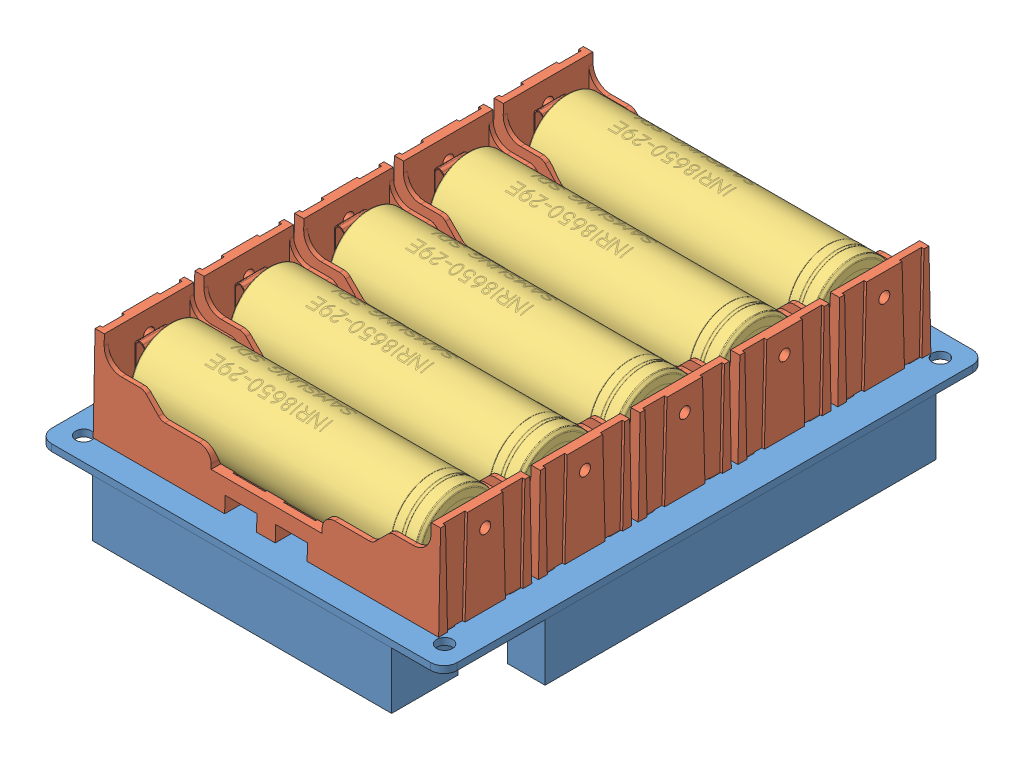
SolidWorks assembly 302 Dayton Audio KAB-BE Battery Board, configuration Default. Lengths in mm.
Overall size (91.5 36.02 122.2).
11 component instances, 3 part files, 16 mates.
Components (placement in the parent):
- 301 Dayton Audio KAB-BE PCB-1: 301 Dayton Audio KAB-BE PCB [Default] at origin size (91.5 14.55 122.2)
- single 18650 battery holder-1: single 18650 battery holder [Défaut] at (0 3.608 54.3158) x (0 0 1) z (-1 0 0) size (21 21.36 77.92)
- single 18650 battery holder-2: single 18650 battery holder [Défaut] at (0 3.608 -31.8158) x (0 0 -1) z (1 0 0) size (21 21.36 77.92)
- single 18650 battery holder-3: single 18650 battery holder [Défaut] at (0 3.608 31.8158) x (0 0 1) z (-1 0 0) size (21 21.36 77.92)
- Samsung INR18650-29R-1: Samsung INR18650-29R [Standard] at (-5.5239 12.8703 22.5) x (0 -0.999726 -0.023395) z (0 -0.023395 0.999726) size (18.38 64.95 18.38)
- Samsung INR18650-29R-2: Samsung INR18650-29R [Standard] at (-5.5239 12.8703 0.01) x (0 -0.999726 -0.023395) z (0 -0.023395 0.999726) size (18.38 64.95 18.38)
- Samsung INR18650-29R-3: Samsung INR18650-29R [Standard] at (-5.5239 12.8703 -22.48) x (0 -0.999726 -0.023395) z (0 -0.023395 0.999726) size (18.38 64.95 18.38)
- single 18650 battery holder-4: single 18650 battery holder [Défaut] at (0 3.608 -9.3158) x (0 0 -1) z (1 0 0) size (21 21.36 77.92)
- Samsung INR18650-29R-4: Samsung INR18650-29R [Standard] at (-5.5239 13.037 44.6724) x (0 -0.995904 -0.090421) z (0 -0.090421 0.995904) size (18.38 64.95 18.38)
- single 18650 battery holder-5: single 18650 battery holder [Défaut] at (0 3.608 9.3158) x (0 0 1) z (-1 0 0) size (21 21.36 77.92)
- Samsung INR18650-29R-5: Samsung INR18650-29R [Standard] at (-5.5239 13.037 -44.6724) x (0 -0.995904 0.090421) z (0 0.090421 0.995904) size (18.38 64.95 18.38)
Mates (geometry in assembly coordinates):
- Coincident1: coordinate: point of 301 Dayton Audio KAB-BE PCB-1; point of assembly
- Coincident2: coincident: plane of 301 Dayton Audio KAB-BE PCB-1 through (0 1.5494 0) normal (0 1 0); plane of single 18650 battery holder-1 through (-37.86 1.5494 6.46) normal (0 -1 0)
- Width1: width: plane of single 18650 battery holder-1 through (36.86 2.1787 10.4917) normal (0 0.020266 0.999795); plane of single 18650 battery holder-1 through (-36.86 2.1787 -10.4917) normal (0 0.020266 -0.999795); plane of 301 Dayton Audio KAB-BE PCB-1 through (45.75 1.5494 61.1) normal (0 0 1); plane of 301 Dayton Audio KAB-BE PCB-1 through (45.75 1.5494 -61.1) normal (0 0 -1)
- Width2: width: plane of single 18650 battery holder-1 through (-38.96 1.7694 9.7) normal (-1 0 0); plane of single 18650 battery holder-1 through (38.96 1.7694 9.7) normal (1 0 0); plane of 301 Dayton Audio KAB-BE PCB-1 through (45.75 1.5494 61.1) normal (1 0 0); plane of 301 Dayton Audio KAB-BE PCB-1 through (-45.75 1.5494 61.1) normal (-1 0 0)
- Coincident3: coincident: plane of 301 Dayton Audio KAB-BE PCB-1 through (0 1.5494 0) normal (0 1 0); plane of single 18650 battery holder-2 through (36.56 1.5494 31.9) normal (0 -1 0)
- Coincident10: coordinate: point of 301 Dayton Audio KAB-BE PCB-1; point of assembly
- Coincident11: coincident: plane of single 18650 battery holder-1 through (38.96 1.7694 -9.7) normal (1 0 0); plane of single 18650 battery holder-2 through (38.96 1.7694 32.2) normal (1 0 0)
- Distance1: distance = 1.5 mm: line of single 18650 battery holder-1 through (38.96 1.7694 10.5) axis (-1 0 0); line of single 18650 battery holder-2 through (9.3 1.7694 12) axis (1 0 0)
- Width3: width: plane of Samsung INR18650-29R-1 through (-32.1 19.6184 22.6579) normal (-1 0 0); plane of Samsung INR18650-29R-1 through (32.1 12.8703 22.5) normal (1 0 0); plane of single 18650 battery holder-2 through (-38.96 1.7694 12.8) normal (-1 0 0); plane of single 18650 battery holder-2 through (38.96 1.7694 12.8) normal (1 0 0)
- Width4: width: plane of single 18650 battery holder-2 through (-36.86 1.7694 19.5) normal (0 0 1); plane of single 18650 battery holder-2 through (36.86 1.7694 25.5) normal (0 0 -1); cylinder of Samsung INR18650-29R-1 through (61.0727 12.8703 22.5) axis (1 0 0) radius 9.16
- Coincident14: coincident: line of single 18650 battery holder-2 through (-2.1 8.7694 30.6908) axis (1 0 0); cylinder of Samsung INR18650-29R-1 through (61.0727 12.8703 22.5) axis (1 0 0) radius 9.16
- Concentric1: concentric: cylinder of single 18650 battery holder-4 through (36.86 13.037 44.6724) axis (-1 0 0) radius 9.5276; cylinder of Samsung INR18650-29R-4 through (61.0727 13.037 44.6724) axis (1 0 0) radius 9.16
- Width5: width: plane of Samsung INR18650-29R-4 through (-32.1 19.7594 45.2827) normal (-1 0 0); plane of Samsung INR18650-29R-4 through (32.1 13.037 44.6724) normal (1 0 0); plane of single 18650 battery holder-4 through (-32.86 18.5094 35.3) normal (1 0 0); plane of single 18650 battery holder-4 through (32.86 18.5094 35.3) normal (-1 0 0)
- Coincident17: coincident: plane of single 18650 battery holder-2 through (-38.96 1.7694 12.8) normal (-1 0 0); plane of single 18650 battery holder-4 through (-38.96 1.7694 35.3) normal (-1 0 0)
- Coincident21: coincident: plane of 301 Dayton Audio KAB-BE PCB-1 through (0 1.5494 0) normal (0 1 0); plane of single 18650 battery holder-4 through (37.86 1.5494 38.54) normal (0 -1 0)
- Distance5: distance = 1.5 mm: line of single 18650 battery holder-4 through (9.3 1.7694 34.5) axis (1 0 0); line of single 18650 battery holder-2 through (38.96 1.7694 33) axis (-1 0 0)
